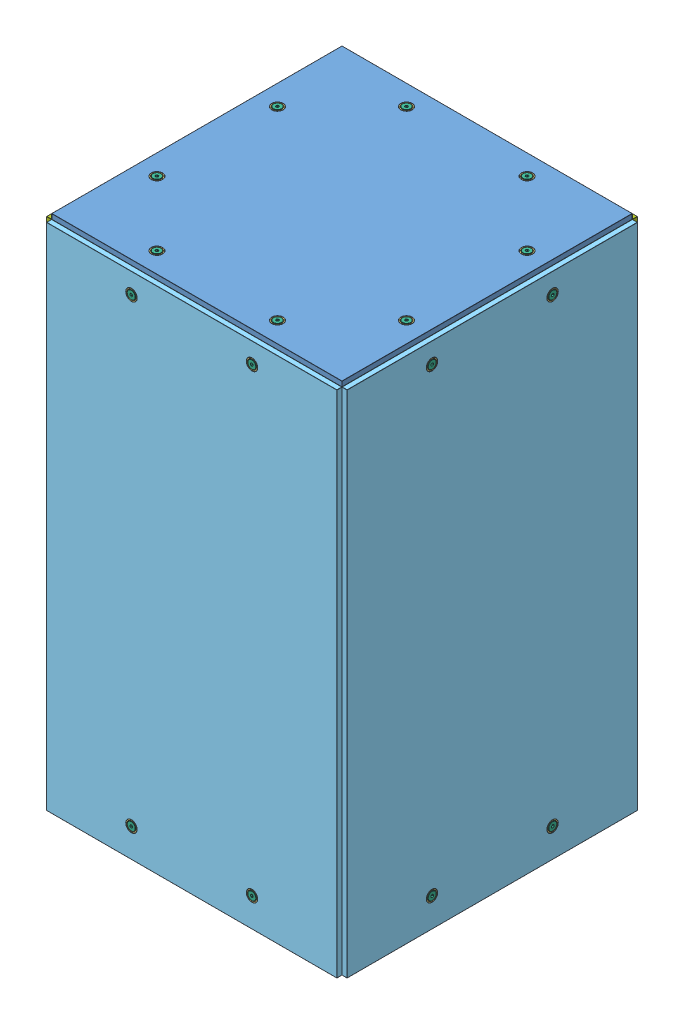
SolidWorks assembly SC.1.GD-PH, configuration Glass Dome 354 x 354 x 600. Lengths in mm.
Overall size (354.53 606.26 354.53).
109 component instances, 7 part files, 60 mates.
Components (placement in the parent):
- SC.1.G.PH.T-1: SC.1.G.PH.T [Topo 342 x 342] at (-2.0067 135.176 -92.8158)
- SC.1.L-1: SC.1.L [Default] at (-80.0067 117.676 60.6842) x (0 0 -1) z (1 0 0)
- SC.1.AC2-1: SC.1.AC2 [Default] at (-73.0067 136.176 54.1842) x (0 -1 0) z (0 0 1)
- SC.1.A2-1: SC.1.A2 [Default] at (-73.0067 133.176 54.1842) x (1 0 0) z (0 1 0)
- SC.1.A2-2: SC.1.A2 [Default] at (-73.0067 131.176 54.1842) x (1 0 0) z (0 1 0)
- SC.1.L-2: SC.1.L [Default] at (151.4933 117.676 -14.8158) x (-1 0 0) z (0 0 -1)
- SC.1.AC2-2: SC.1.AC2 [Default] at (144.9933 136.176 -21.8158) x (0 -1 0) z (0 0 1)
- SC.1.A2-3: SC.1.A2 [Default] at (144.9933 131.176 -21.8158) x (1 0 0) z (0 1 0)
- SC.1.A2-4: SC.1.A2 [Default] at (144.9933 133.176 -21.8158) x (1 0 0) z (0 1 0)
- SC.1.AC2-3: SC.1.AC2 [Default] at (68.9933 136.176 54.1842) x (0 -1 0) z (0 0 -1)
- SC.1.A2-5: SC.1.A2 [Default] at (68.9933 135.176 54.1842) x (-1 0 0) z (0 -1 0)
- SC.1.A2-6: SC.1.A2 [Default] at (68.9933 133.176 54.1842) x (-1 0 0) z (0 -1 0)
- SC.1.L-3: SC.1.L [Default] at (61.9933 117.676 60.6842) x (0 0 -1) z (1 0 0)
- SC.1.AC2-4: SC.1.AC2 [Default] at (144.9933 136.176 -163.8158) x (0 -1 0) z (0 0 1)
- SC.1.A2-7: SC.1.A2 [Default] at (144.9933 135.176 -163.8158) x (1 0 0) z (0 -1 0)
- SC.1.A2-8: SC.1.A2 [Default] at (144.9933 133.176 -163.8158) x (1 0 0) z (0 -1 0)
- SC.1.L-4: SC.1.L [Default] at (151.4933 117.676 -156.8158) x (-1 0 0) z (0 0 -1)
- SC.1.AC2-5: SC.1.AC2 [Default] at (-149.0067 136.176 -21.8158) x (0 -1 0) z (0 0 -1)
- SC.1.A2-9: SC.1.A2 [Default] at (-149.0067 135.176 -21.8158) x (-1 0 0) z (0 -1 0)
- SC.1.A2-10: SC.1.A2 [Default] at (-149.0067 133.176 -21.8158) x (-1 0 0) z (0 -1 0)
- SC.1.L-5: SC.1.L [Default] at (-155.5067 117.676 -28.8158)
- SC.1.AC2-6: SC.1.AC2 [Default] at (-149.0067 136.176 -163.8158) x (0 -1 0) z (0 0 -1)
- SC.1.A2-11: SC.1.A2 [Default] at (-149.0067 133.176 -163.8158) x (-1 0 0) z (0 1 0)
- SC.1.A2-12: SC.1.A2 [Default] at (-149.0067 131.176 -163.8158) x (-1 0 0) z (0 1 0)
- SC.1.L-6: SC.1.L [Default] at (-155.5067 117.676 -170.8158)
- SC.1.AC2-7: SC.1.AC2 [Default] at (68.9933 136.176 -239.8158) x (0 -1 0) z (0 0 -1)
- SC.1.A2-13: SC.1.A2 [Default] at (68.9933 133.176 -239.8158) x (-1 0 0) z (0 1 0)
- SC.1.A2-14: SC.1.A2 [Default] at (68.9933 131.176 -239.8158) x (-1 0 0) z (0 1 0)
- SC.1.L-7: SC.1.L [Default] at (75.9933 117.676 -246.3158) x (0 0 1) z (-1 0 0)
- SC.1.AC2-8: SC.1.AC2 [Default] at (-73.0067 136.176 -239.8158) x (0 -1 0) z (0 0 1)
- SC.1.A2-15: SC.1.A2 [Default] at (-73.0067 135.176 -239.8158) x (1 0 0) z (0 -1 0)
- SC.1.A2-16: SC.1.A2 [Default] at (-73.0067 133.176 -239.8158) x (1 0 0) z (0 -1 0)
- SC.1.L-8: SC.1.L [Default] at (-66.0067 117.676 -246.3158) x (0 0 1) z (-1 0 0)
- SC.1.A2-20: SC.1.A2 [Default] at (-73.0067 111.176 74.1842)
- SC.1.A2-21: SC.1.A2 [Default] at (-73.0067 111.176 76.1842)
- SC.1.G.PH.L-1: SC.1.G.PH.L [Lateral 342 x 600] at (-2.0067 -164.824 78.1842)
- SC.1.A2-22: SC.1.A2 [Default] at (166.9933 111.176 -21.8158) x (0 0 -1) z (1 0 0)
- SC.1.A2-23: SC.1.A2 [Default] at (164.9933 111.176 -21.8158) x (0 0 -1) z (1 0 0)
- SC.1.G.PH.L-5: SC.1.G.PH.L [Lateral 342 x 600] at (168.9933 -164.824 -92.8158) x (0 0 -1) z (1 0 0)
- SC.1.AC2-10: SC.1.AC2 [Default] at (-73.0067 111.176 79.1842) x (0 0 -1) z (0 -1 0)
- SC.1.AC2-11: SC.1.AC2 [Default] at (169.9933 111.176 -21.8158) x (-1 0 0) z (0 0 1)
- SC.1.P7991-12-1: SC.1.P7991-12 [ISO 10642 - M5 x 12 --- 12N] at (-73.0067 141.4402 54.1842) x (0 -1 0) z (0 0 1)
- SC.1.P7991-12-17: SC.1.P7991-12 [ISO 10642 - M5 x 12 --- 12N] at (-73.0067 111.176 84.4484) x (0 0 -1) z (0 -1 0)
- SC.1.P7991-12-21: SC.1.P7991-12 [ISO 10642 - M5 x 12 --- 12N] at (144.9933 141.4402 -21.8158) x (0 -1 0) z (0 0 1)
- SC.1.P7991-12-25: SC.1.P7991-12 [ISO 10642 - M5 x 12 --- 12N] at (175.2575 111.176 -21.8158) x (-1 0 0) z (0 0 1)
- SC.1.P7991-12-5: SC.1.P7991-12 [ISO 10642 - M5 x 12 --- 12N] at (68.9933 141.4402 54.1842) x (0 -1 0) z (0 0 -1)
- SC.1.P7991-12-18: SC.1.P7991-12 [ISO 10642 - M5 x 12 --- 12N] at (68.9933 111.176 84.4484) x (0 0 -1) z (0 1 0)
- SC.1.AC2-12: SC.1.AC2 [Default] at (68.9933 111.176 79.1842) x (0 0 -1) z (0 1 0)
- SC.1.A2-24: SC.1.A2 [Default] at (68.9933 111.176 78.1842) x (-1 0 0) z (0 0 -1)
- SC.1.A2-25: SC.1.A2 [Default] at (68.9933 111.176 76.1842) x (-1 0 0) z (0 0 -1)
- SC.1.P7991-12-22: SC.1.P7991-12 [ISO 10642 - M5 x 12 --- 12N] at (144.9933 141.4402 -163.8158) x (0 -1 0) z (0 0 1)
- SC.1.P7991-12-26: SC.1.P7991-12 [ISO 10642 - M5 x 12 --- 12N] at (175.2575 111.176 -163.8158) x (-1 0 0) z (0 0 1)
- SC.1.AC2-13: SC.1.AC2 [Default] at (169.9933 111.176 -163.8158) x (-1 0 0) z (0 0 1)
- SC.1.A2-26: SC.1.A2 [Default] at (168.9933 111.176 -163.8158) x (0 0 1) z (-1 0 0)
- SC.1.A2-27: SC.1.A2 [Default] at (166.9933 111.176 -163.8158) x (0 0 1) z (-1 0 0)
- SC.1.P7991-12-24: SC.1.P7991-12 [ISO 10642 - M5 x 12 --- 12N] at (-149.0067 141.4402 -21.8158) x (0 -1 0) z (0 0 -1)
- SC.1.A2-28: SC.1.A2 [Default] at (-173.0067 111.176 -21.8158) x (0 0 -1) z (1 0 0)
- SC.1.A2-29: SC.1.A2 [Default] at (-171.0067 111.176 -21.8158) x (0 0 -1) z (1 0 0)
- SC.1.AC2-14: SC.1.AC2 [Default] at (-174.0067 111.176 -21.8158) x (1 0 0) z (0 0 -1)
- SC.1.P7991-12-28: SC.1.P7991-12 [ISO 10642 - M5 x 12 --- 12N] at (-179.2709 111.176 -21.8158) x (1 0 0) z (0 0 -1)
- MirrorSC.1.G.PH.L-6: MirrorSC.1.G.PH.L [Lateral 342 x 600] at (-173.0067 -164.824 -92.8158) x (0 0 -1) z (1 0 0)
- SC.1.P7991-12-27: SC.1.P7991-12 [ISO 10642 - M5 x 12 --- 12N] at (-179.2709 111.176 -163.8158) x (1 0 0) z (0 0 -1)
- SC.1.AC2-15: SC.1.AC2 [Default] at (-174.0067 111.176 -163.8158) x (1 0 0) z (0 0 -1)
- SC.1.P7991-12-23: SC.1.P7991-12 [ISO 10642 - M5 x 12 --- 12N] at (-149.0067 141.4402 -163.8158) x (0 -1 0) z (0 0 -1)
- SC.1.P7991-12-20: SC.1.P7991-12 [ISO 10642 - M5 x 12 --- 12N] at (-73.0067 111.176 -270.08) x (0 0 1) z (0 1 0)
- SC.1.AC2-16: SC.1.AC2 [Default] at (-73.0067 111.176 -264.8158) x (0 0 1) z (0 1 0)
- SC.1.A2-30: SC.1.A2 [Default] at (-73.0067 111.176 -263.8158)
- SC.1.A2-31: SC.1.A2 [Default] at (-73.0067 111.176 -261.8158)
- SC.1.P7991-12-16: SC.1.P7991-12 [ISO 10642 - M5 x 12 --- 12N] at (-73.0067 141.4402 -239.8158) x (0 -1 0) z (0 0 1)
- SC.1.P7991-12-15: SC.1.P7991-12 [ISO 10642 - M5 x 12 --- 12N] at (68.9933 141.4402 -239.8158) x (0 -1 0) z (0 0 -1)
- SC.1.A2-32: SC.1.A2 [Default] at (68.9933 111.176 -261.8158) x (-1 0 0) z (0 0 -1)
- SC.1.A2-33: SC.1.A2 [Default] at (68.9933 111.176 -259.8158) x (-1 0 0) z (0 0 -1)
- SC.1.P7991-12-19: SC.1.P7991-12 [ISO 10642 - M5 x 12 --- 12N] at (68.9933 111.176 -270.08) x (0 0 1) z (0 -1 0)
- SC.1.AC2-17: SC.1.AC2 [Default] at (68.9933 111.176 -264.8158) x (0 0 1) z (0 -1 0)
- MirrorSC.1.G.PH.L-7: MirrorSC.1.G.PH.L [Lateral 342 x 600] at (-2.0067 -164.824 -263.8158)
- SC.1.P7991-12-29: SC.1.P7991-12 [ISO 10642 - M5 x 12 --- 12N] at (-73.0067 -430.824 84.4484) x (0 0 -1) z (0 -1 0)
- SC.1.AC2-18: SC.1.AC2 [Default] at (-73.0067 -430.824 79.1842) x (0 0 -1) z (0 -1 0)
- SC.1.A2-34: SC.1.A2 [Default] at (-73.0067 -430.824 74.1842)
- SC.1.A2-35: SC.1.A2 [Default] at (-73.0067 -430.824 76.1842)
- SC.1.P7991-12-33: SC.1.P7991-12 [ISO 10642 - M5 x 12 --- 12N] at (175.2575 -430.824 -21.8158) x (-1 0 0) z (0 0 1)
- SC.1.AC2-19: SC.1.AC2 [Default] at (169.9933 -430.824 -21.8158) x (-1 0 0) z (0 0 1)
- SC.1.A2-36: SC.1.A2 [Default] at (164.9933 -430.824 -21.8158) x (0 -1 0) z (1 0 0)
- SC.1.A2-37: SC.1.A2 [Default] at (166.9933 -430.824 -21.8158) x (0 -1 0) z (1 0 0)
- SC.1.P7991-12-30: SC.1.P7991-12 [ISO 10642 - M5 x 12 --- 12N] at (68.9933 -430.824 84.4484) x (0 0 -1) z (0 1 0)
- SC.1.AC2-20: SC.1.AC2 [Default] at (68.9933 -430.824 79.1842) x (0 0 -1) z (0 1 0)
- SC.1.A2-38: SC.1.A2 [Default] at (68.9933 -430.824 78.1842) x (-1 0 0) z (0 0 -1)
- SC.1.A2-39: SC.1.A2 [Default] at (68.9933 -430.824 76.1842) x (-1 0 0) z (0 0 -1)
- SC.1.P7991-12-34: SC.1.P7991-12 [ISO 10642 - M5 x 12 --- 12N] at (175.2575 -430.824 -163.8158) x (-1 0 0) z (0 0 1)
- SC.1.AC2-21: SC.1.AC2 [Default] at (169.9933 -430.824 -163.8158) x (-1 0 0) z (0 0 1)
- SC.1.A2-40: SC.1.A2 [Default] at (168.9933 -430.824 -163.8158) x (0 -1 0) z (-1 0 0)
- SC.1.A2-41: SC.1.A2 [Default] at (166.9933 -430.824 -163.8158) x (0 -1 0) z (-1 0 0)
- SC.1.P7991-12-36: SC.1.P7991-12 [ISO 10642 - M5 x 12 --- 12N] at (-179.2709 -430.824 -21.8158) x (1 0 0) z (0 0 -1)
- SC.1.AC2-22: SC.1.AC2 [Default] at (-174.0067 -430.824 -21.8158) x (1 0 0) z (0 0 -1)
- SC.1.P7991-12-35: SC.1.P7991-12 [ISO 10642 - M5 x 12 --- 12N] at (-179.2709 -430.824 -163.8158) x (1 0 0) z (0 0 -1)
- SC.1.AC2-23: SC.1.AC2 [Default] at (-174.0067 -430.824 -163.8158) x (1 0 0) z (0 0 -1)
- SC.1.A2-42: SC.1.A2 [Default] at (-171.0067 -430.824 -163.8158) x (0 -1 0) z (-1 0 0)
- SC.1.A2-43: SC.1.A2 [Default] at (-169.0067 -430.824 -163.8158) x (0 -1 0) z (-1 0 0)
- SC.1.A2-44: SC.1.A2 [Default] at (-173.0067 -430.824 -21.8158) x (0 -1 0) z (1 0 0)
- SC.1.A2-45: SC.1.A2 [Default] at (-171.0067 -430.824 -21.8158) x (0 -1 0) z (1 0 0)
- SC.1.A2-46: SC.1.A2 [Default] at (-171.0067 111.176 -163.8158) x (0 0 1) z (-1 0 0)
- SC.1.A2-47: SC.1.A2 [Default] at (-169.0067 111.176 -163.8158) x (0 0 1) z (-1 0 0)
- SC.1.AC2-24: SC.1.AC2 [Default] at (-73.0067 -430.824 -264.8158) x (0 0 1) z (0 1 0)
- SC.1.A2-48: SC.1.A2 [Default] at (-73.0067 -430.824 -263.8158)
- SC.1.A2-49: SC.1.A2 [Default] at (-73.0067 -430.824 -261.8158)
- SC.1.P7991-12-32: SC.1.P7991-12 [ISO 10642 - M5 x 12 --- 12N] at (-73.0067 -430.824 -270.08) x (0 0 1) z (0 1 0)
- SC.1.AC2-25: SC.1.AC2 [Default] at (68.9933 -430.824 -264.8158) x (0 0 1) z (0 -1 0)
- SC.1.A2-50: SC.1.A2 [Default] at (68.9933 -430.824 -261.8158) x (-1 0 0) z (0 0 -1)
- SC.1.A2-51: SC.1.A2 [Default] at (68.9933 -430.824 -259.8158) x (-1 0 0) z (0 0 -1)
- SC.1.P7991-12-31: SC.1.P7991-12 [ISO 10642 - M5 x 12 --- 12N] at (68.9933 -430.824 -270.08) x (0 0 1) z (0 -1 0)
Mates (geometry in assembly coordinates):
- Concentric3: concentric aligned: cylinder of SC.1.G.PH.T-1 through (-73.0067 135.176 54.1842) axis (0 1 0) radius 4; cylinder of SC.1.AC2-1 through (-73.0067 145.0904 54.1842) axis (0 1 0) radius 4
- Coincident2: coincident aligned: cone of SC.1.G.PH.T-1 through (-73.0067 138.426 54.1842) axis (0 -1 0); cone of SC.1.AC2-1 through (-73.0067 138.426 54.1842) axis (0 -1 0)
- Coincident3: coincident anti-aligned: plane of SC.1.G.PH.T-1 through (-2.0067 135.176 -92.8158) normal (0 -1 0); plane of SC.1.A2-1 through (-73.0067 135.176 54.1842) normal (0 1 0)
- Concentric5: concentric anti-aligned: cylinder of SC.1.AC2-1 through (-73.0067 145.0904 54.1842) axis (0 1 0) radius 4; cylinder of SC.1.A2-1 through (-73.0067 135.176 54.1842) axis (0 -1 0) radius 4
- Coincident4: coincident anti-aligned: plane of SC.1.A2-1 through (-73.0067 133.176 54.1842) normal (0 -1 0); plane of SC.1.A2-2 through (-73.0067 133.176 54.1842) normal (0 1 0)
- Concentric6: concentric anti-aligned: cylinder of SC.1.AC2-1 through (-73.0067 145.0904 54.1842) axis (0 1 0) radius 4; cylinder of SC.1.A2-2 through (-73.0067 133.176 54.1842) axis (0 -1 0) radius 4
- Coincident5: coincident anti-aligned: plane of SC.1.L-1 through (-66.0067 131.176 47.1842) normal (0 1 0); plane of SC.1.A2-2 through (-73.0067 131.176 54.1842) normal (0 -1 0)
- Concentric7: concentric aligned: cylinder of SC.1.L-1 through (-73.0067 131.176 54.1842) axis (0 1 0) radius 2.1; cylinder of SC.1.AC2-1 through (-73.0067 145.0904 54.1842) axis (0 1 0) radius 4
- Parallel1: parallel aligned: plane of SC.1.G.PH.T-1 through (-173.0067 141.176 78.1842) normal (0 0 1); plane of SC.1.L-1 through (-66.0067 131.176 74.1842) normal (0 0 1)
- Concentric8: concentric anti-aligned: cylinder of SC.1.AC2-2 through (144.9933 145.0904 -21.8158) axis (0 1 0) radius 4; cylinder of SC.1.A2-4 through (144.9933 135.176 -21.8158) axis (0 -1 0) radius 4
- Coincident7: coincident anti-aligned: plane of SC.1.A2-3 through (144.9933 133.176 -21.8158) normal (0 1 0); plane of SC.1.A2-4 through (144.9933 133.176 -21.8158) normal (0 -1 0)
- Concentric9: concentric anti-aligned: cylinder of SC.1.AC2-2 through (144.9933 145.0904 -21.8158) axis (0 1 0) radius 4; cylinder of SC.1.A2-3 through (144.9933 133.176 -21.8158) axis (0 -1 0) radius 4
- Coincident8: coincident anti-aligned: plane of SC.1.L-2 through (137.9933 131.176 -28.8158) normal (0 1 0); plane of SC.1.A2-3 through (144.9933 131.176 -21.8158) normal (0 -1 0)
- Concentric10: concentric aligned: cylinder of SC.1.L-2 through (144.9933 131.176 -21.8158) axis (0 1 0) radius 2.1; cylinder of SC.1.AC2-2 through (144.9933 145.0904 -21.8158) axis (0 1 0) radius 4
- Concentric11: concentric aligned: cylinder of SC.1.G.PH.T-1 through (144.9933 135.176 -21.8158) axis (0 1 0) radius 4; cylinder of SC.1.AC2-2 through (144.9933 145.0904 -21.8158) axis (0 1 0) radius 4
- Coincident9: coincident aligned: cone of SC.1.G.PH.T-1 through (144.9933 138.426 -21.8158) axis (0 -1 0); cone of SC.1.AC2-2 through (144.9933 138.426 -21.8158) axis (0 -1 0)
- Coincident10: coincident anti-aligned: plane of SC.1.G.PH.T-1 through (-2.0067 135.176 -92.8158) normal (0 -1 0); plane of SC.1.A2-4 through (144.9933 135.176 -21.8158) normal (0 1 0)
- Parallel2: parallel aligned: plane of SC.1.G.PH.T-1 through (168.9933 141.176 -263.8158) normal (1 0 0); plane of SC.1.L-2 through (164.9933 131.176 -28.8158) normal (1 0 0)
- Coincident15: coincident anti-aligned: plane of SC.1.L-1 through (-66.0067 131.176 74.1842) normal (0 0 1); plane of SC.1.A2-20 through (-73.0067 111.176 74.1842) normal (0 0 -1)
- Concentric14: concentric anti-aligned: cylinder of SC.1.L-1 through (-73.0067 111.176 74.1842) axis (0 0 1) radius 2.1; cylinder of SC.1.A2-20 through (-73.0067 111.176 76.1842) axis (0 0 -1) radius 4
- Coincident16: coincident anti-aligned: plane of SC.1.A2-20 through (-73.0067 111.176 76.1842) normal (0 0 1); plane of SC.1.A2-21 through (-73.0067 111.176 76.1842) normal (0 0 -1)
- Concentric15: concentric aligned: cylinder of SC.1.A2-20 through (-73.0067 111.176 76.1842) axis (0 0 -1) radius 4; cylinder of SC.1.A2-21 through (-73.0067 111.176 78.1842) axis (0 0 -1) radius 4
- Coincident17: coincident anti-aligned: plane of SC.1.A2-21 through (-73.0067 111.176 78.1842) normal (0 0 1); plane of SC.1.G.PH.L-1 through (-2.0067 -164.824 78.1842) normal (0 0 -1)
- Concentric16: concentric aligned: cylinder of SC.1.L-1 through (-73.0067 111.176 74.1842) axis (0 0 1) radius 2.1; cylinder of SC.1.G.PH.L-1 through (-73.0067 111.176 78.1842) axis (0 0 1) radius 4
- Concentric17: concentric aligned: cylinder of SC.1.L-3 through (68.9933 111.176 74.1842) axis (0 0 1) radius 2.1; cylinder of SC.1.G.PH.L-1 through (68.9933 111.176 78.1842) axis (0 0 1) radius 4
- Coincident18: coincident anti-aligned: plane of SC.1.A2-22 through (166.9933 111.176 -21.8158) normal (-1 0 0); plane of SC.1.A2-23 through (166.9933 111.176 -21.8158) normal (1 0 0)
- Concentric18: concentric aligned: cylinder of SC.1.A2-22 through (168.9933 111.176 -21.8158) axis (-1 0 0) radius 4; cylinder of SC.1.A2-23 through (166.9933 111.176 -21.8158) axis (-1 0 0) radius 4
- Coincident19: coincident anti-aligned: plane of SC.1.L-2 through (164.9933 131.176 -28.8158) normal (1 0 0); plane of SC.1.A2-23 through (164.9933 111.176 -21.8158) normal (-1 0 0)
- Concentric19: concentric anti-aligned: cylinder of SC.1.L-2 through (164.9933 111.176 -21.8158) axis (1 0 0) radius 2.1; cylinder of SC.1.A2-23 through (166.9933 111.176 -21.8158) axis (-1 0 0) radius 4
- Coincident20: coincident anti-aligned: plane of SC.1.A2-22 through (168.9933 111.176 -21.8158) normal (1 0 0); plane of SC.1.G.PH.L-5 through (168.9933 -164.824 -92.8158) normal (-1 0 0)
- Concentric20: concentric aligned: cylinder of SC.1.L-2 through (164.9933 111.176 -21.8158) axis (1 0 0) radius 2.1; cylinder of SC.1.G.PH.L-5 through (168.9933 111.176 -21.8158) axis (1 0 0) radius 4
- Concentric21: concentric aligned: cylinder of SC.1.L-4 through (164.9933 111.176 -163.8158) axis (1 0 0) radius 2.1; cylinder of SC.1.G.PH.L-5 through (168.9933 111.176 -163.8158) axis (1 0 0) radius 4
- Concentric22: concentric aligned: cylinder of SC.1.G.PH.L-1 through (-73.0067 111.176 78.1842) axis (0 0 1) radius 4; cylinder of SC.1.AC2-10 through (-73.0067 111.176 88.0987) axis (0 0 1) radius 4
- Coincident21: coincident aligned: cone of SC.1.G.PH.L-1 through (-73.0067 111.176 81.4342) axis (0 0 -1); cone of SC.1.AC2-10 through (-73.0067 111.176 81.4342) axis (0 0 -1)
- Concentric23: concentric aligned: cylinder of SC.1.G.PH.L-5 through (168.9933 111.176 -21.8158) axis (1 0 0) radius 4; cylinder of SC.1.AC2-11 through (178.9077 111.176 -21.8158) axis (1 0 0) radius 4
- Coincident22: coincident aligned: cone of SC.1.G.PH.L-5 through (172.2433 111.176 -21.8158) axis (-1 0 0); cone of SC.1.AC2-11 through (172.2433 111.176 -21.8158) axis (-1 0 0)
- Concentric24: concentric aligned: cylinder of SC.1.P7991-12-1 through (-73.0067 141.4402 54.1842) axis (0 1 0) radius 2.5; cylinder of SC.1.AC2-1 through (-73.0067 145.0904 54.1842) axis (0 1 0) radius 4
- Coincident23: coincident aligned: cone of SC.1.AC2-1 through (-73.0067 141.176 54.1842) axis (0 -1 0); cone of SC.1.P7991-12-1 through (-73.0067 140.5552 54.1842) axis (0 -1 0)
- Concentric26: concentric aligned: cylinder of SC.1.P7991-12-17 through (-73.0067 111.176 84.4484) axis (0 0 1) radius 2.5; cylinder of SC.1.AC2-10 through (-73.0067 111.176 88.0987) axis (0 0 1) radius 4
- Coincident24: coincident aligned: cone of SC.1.AC2-10 through (-73.0067 111.176 84.1842) axis (0 0 -1); cone of SC.1.P7991-12-17 through (-73.0067 111.176 83.5634) axis (0 0 -1)
- Concentric27: concentric aligned: cylinder of SC.1.P7991-12-21 through (144.9933 141.4402 -21.8158) axis (0 1 0) radius 2.5; cylinder of SC.1.AC2-2 through (144.9933 145.0904 -21.8158) axis (0 1 0) radius 4
- Coincident25: coincident aligned: cone of SC.1.AC2-2 through (144.9933 141.176 -21.8158) axis (0 -1 0); cone of SC.1.P7991-12-21 through (144.9933 140.5552 -21.8158) axis (0 -1 0)
- Concentric28: concentric aligned: cylinder of SC.1.P7991-12-25 through (175.2575 111.176 -21.8158) axis (1 0 0) radius 2.5; cylinder of SC.1.AC2-11 through (178.9077 111.176 -21.8158) axis (1 0 0) radius 4
- Coincident26: coincident aligned: cone of SC.1.AC2-11 through (174.9933 111.176 -21.8158) axis (-1 0 0); cone of SC.1.P7991-12-25 through (174.3725 111.176 -21.8158) axis (-1 0 0)
- Concentric29: concentric anti-aligned: cylinder of SC.1.AC2-18 through (-73.0067 -430.824 88.0987) axis (0 0 1) radius 4; cylinder of SC.1.A2-35 through (-73.0067 -430.824 78.1842) axis (0 0 -1) radius 4
- Coincident27: coincident anti-aligned: plane of SC.1.A2-34 through (-73.0067 -430.824 76.1842) normal (0 0 1); plane of SC.1.A2-35 through (-73.0067 -430.824 76.1842) normal (0 0 -1)
- Concentric30: concentric anti-aligned: cylinder of SC.1.AC2-18 through (-73.0067 -430.824 88.0987) axis (0 0 1) radius 4; cylinder of SC.1.A2-34 through (-73.0067 -430.824 76.1842) axis (0 0 -1) radius 4
- Concentric31: concentric aligned: cylinder of SC.1.P7991-12-29 through (-73.0067 -430.824 84.4484) axis (0 0 1) radius 2.5; cylinder of SC.1.AC2-18 through (-73.0067 -430.824 88.0987) axis (0 0 1) radius 4
- Coincident28: coincident aligned: cone of SC.1.P7991-12-29 through (-73.0067 -430.824 83.5634) axis (0 0 -1); cone of SC.1.AC2-18 through (-73.0067 -430.824 84.1842) axis (0 0 -1)
- Concentric32: concentric aligned: cylinder of SC.1.G.PH.L-1 through (-73.0067 -430.824 78.1842) axis (0 0 1) radius 4; cylinder of SC.1.AC2-18 through (-73.0067 -430.824 88.0987) axis (0 0 1) radius 4
- Coincident29: coincident aligned: cone of SC.1.G.PH.L-1 through (-73.0067 -430.824 81.4342) axis (0 0 -1); cone of SC.1.AC2-18 through (-73.0067 -430.824 81.4342) axis (0 0 -1)
- Coincident30: coincident anti-aligned: plane of SC.1.G.PH.L-1 through (-2.0067 -164.824 78.1842) normal (0 0 -1); plane of SC.1.A2-35 through (-73.0067 -430.824 78.1842) normal (0 0 1)
- Concentric33: concentric anti-aligned: cylinder of SC.1.AC2-19 through (178.9077 -430.824 -21.8158) axis (1 0 0) radius 4; cylinder of SC.1.A2-37 through (168.9933 -430.824 -21.8158) axis (-1 0 0) radius 4
- Coincident31: coincident anti-aligned: plane of SC.1.A2-36 through (166.9933 -430.824 -21.8158) normal (1 0 0); plane of SC.1.A2-37 through (166.9933 -430.824 -21.8158) normal (-1 0 0)
- Concentric34: concentric anti-aligned: cylinder of SC.1.AC2-19 through (178.9077 -430.824 -21.8158) axis (1 0 0) radius 4; cylinder of SC.1.A2-36 through (166.9933 -430.824 -21.8158) axis (-1 0 0) radius 4
- Concentric35: concentric aligned: cylinder of ? through (174.6968 -430.824 -21.8158) axis (1 0 0) radius 2.5; cylinder of SC.1.AC2-19 through (178.9077 -430.824 -21.8158) axis (1 0 0) radius 4
- Coincident32: coincident aligned: cone of SC.1.P7991-12-33 through (174.3725 -430.824 -21.8158) axis (-1 0 0); cone of SC.1.AC2-19 through (174.9933 -430.824 -21.8158) axis (-1 0 0)
- Concentric36: concentric aligned: cylinder of SC.1.G.PH.L-5 through (168.9933 -430.824 -21.8158) axis (1 0 0) radius 4; cylinder of SC.1.AC2-19 through (178.9077 -430.824 -21.8158) axis (1 0 0) radius 4
- Coincident33: coincident aligned: cone of SC.1.G.PH.L-5 through (172.2433 -430.824 -21.8158) axis (-1 0 0); cone of SC.1.AC2-19 through (172.2433 -430.824 -21.8158) axis (-1 0 0)
- Coincident34: coincident anti-aligned: plane of SC.1.G.PH.L-5 through (168.9933 -164.824 -92.8158) normal (-1 0 0); plane of SC.1.A2-37 through (168.9933 -430.824 -21.8158) normal (1 0 0)
